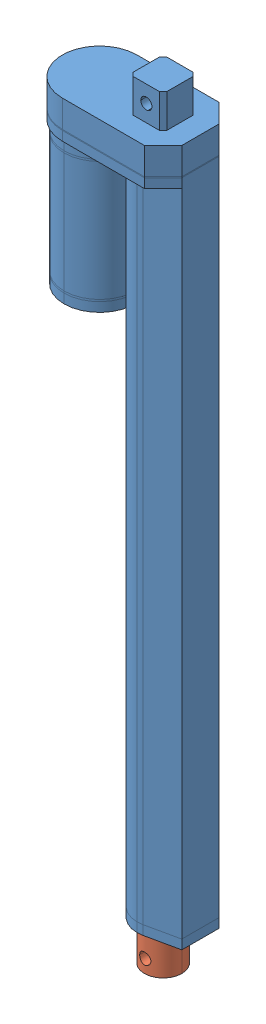
SolidWorks assembly Assem3, configuration Default. Lengths in mm.
Overall size (74 412 40).
2 component instances, 2 part files, 3 mates.
Components (placement in the parent):
- 300mm Body.step-1: 300mm Body.step [Default] at (136.2675 383.5385 309.1578) size (74 391 40)
- 300mm Rod.step-1: 300mm Rod.step [Default] at (143.2675 -10.4615 309.1578) x (0 0 -1) z (1 0 0) size (20.01 321 20)
Mates (geometry in assembly coordinates):
- LimitDistance1: limit distance = 21 mm aligned: plane of 300mm Rod.step-1 through (143.2675 -10.4615 309.1578) normal (0 -1 0); plane of 300mm Body.step-1 through (143.2675 10.5385 309.1578) normal (0 -1 0)
- Concentric1: concentric aligned: cylinder of 300mm Body.step-1 through (143.2675 391.8228 309.1578) axis (0 -1 0) radius 10; cylinder of 300mm Rod.step-1 through (143.2675 310.5385 309.1578) axis (0 -1 0) radius 10
- Parallel1: parallel anti-aligned: cylinder of 300mm Body.step-1 through (143.2675 392.5385 291.6726) axis (0 0 1) radius 3; cylinder of 300mm Rod.step-1 through (143.2675 -3.4615 319.1588) axis (0 0 -1) radius 3
